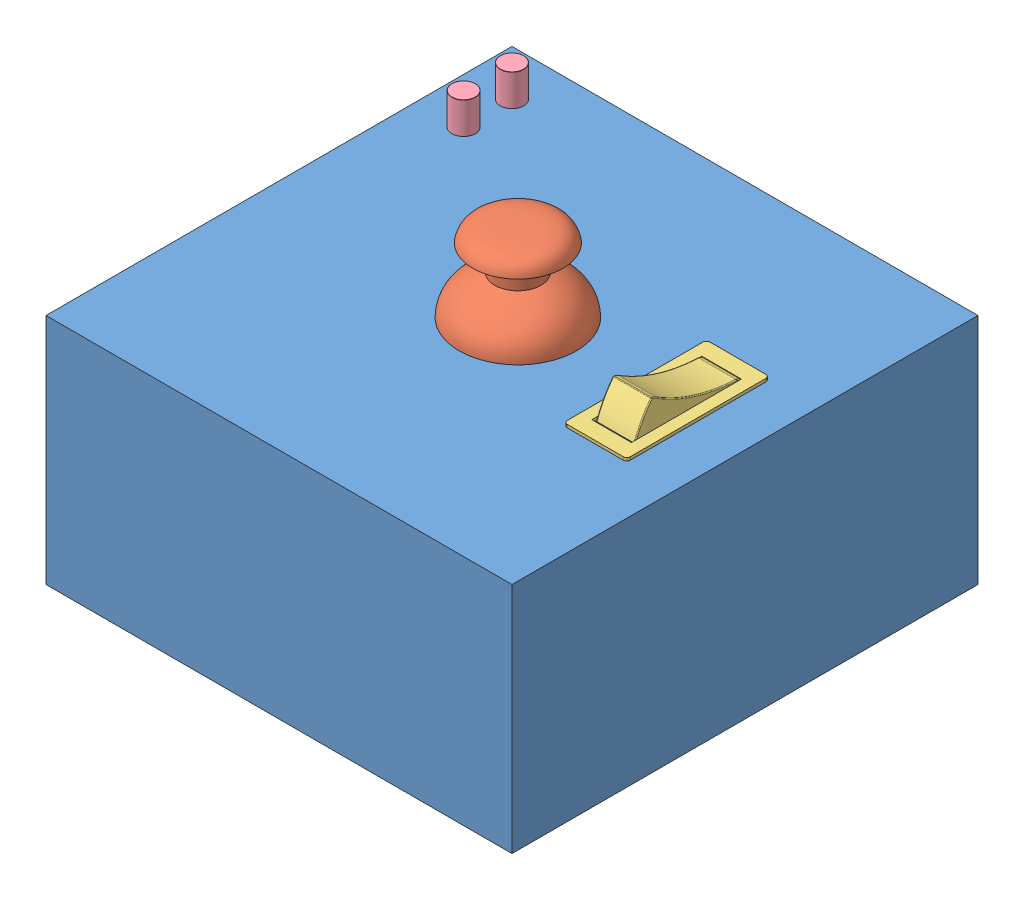
SolidWorks assembly joystick, configuration Default. Lengths in mm.
Overall size (100 67.28 100).
5 component instances, 4 part files, 0 mates.
Components (placement in the parent):
- base-1: base [Default] at (-5.3806 25.0974 124.3292) size (100 50 100)
- PS2 Joystick Module-1: PS2 Joystick Module [Default] at (45.552 61.4228 79.4473) x (0 0 -1) z (1 0 0) size (44.71 32.6 30.3)
- switch-1: switch [Default] at (73.7131 56.2441 36.7393) x (0 0 -1) z (1 0 0) size (32.5 37.98 13.5)
- LUCKYLIGHT LL-504BD2Q-B4-2B v2.step-1: LUCKYLIGHT LL-504BD2Q-B4-2B v2.step [Default] at (4.4479 75.1595 34.1636) size (5.05 13.8 5.05)
- LUCKYLIGHT LL-504BD2Q-B4-2B v2.step-2: LUCKYLIGHT LL-504BD2Q-B4-2B v2.step [Default] at (4.4479 75.1595 44.5421) size (5.05 13.8 5.05)
